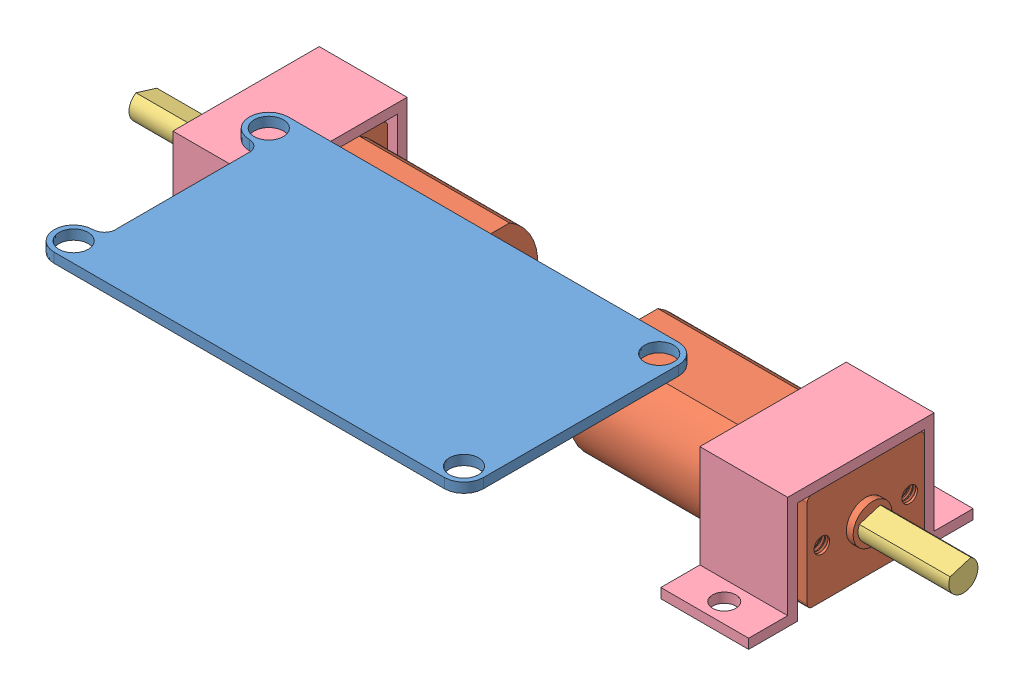
SolidWorks assembly Assem2, configuration Default. Lengths in mm.
Overall size (84 18.94 43.27).
9 component instances, 4 part files, 9 mates.
Components (placement in the parent):
- Spark (Controller)-1: Spark (Controller) [Default] at (-80.2087 -0.5 -49.4214) size (44 1 24)
- Motor_Assembly-1: Motor_Assembly [Default] at (-124.5843 -37.3995 -83.678) x (0 0 1) z (-1 0 0) size (12 10 39.5)
  - Motor_Gearbox-1: Motor_Gearbox [Default] at (14.9911 24.4599 -12.2783) size (12 10 25.9)
  - Motor_Gearbox_Driveshaft-1: Motor_Gearbox_Driveshaft [Default] at (14.9911 24.4599 -41.7783) x (0.956114 0.292994 0) z (0 0 1) size (3 2.5 39.5)
- Motor_Assembly-2: Motor_Assembly [Default] at (-36.0278 -37.3995 -53.6959) x (0 0 -1) z (1 0 0) size (12 10 39.5)
  - Motor_Gearbox-1: Motor_Gearbox [Default] at (14.9911 24.4599 -12.2783) size (12 10 25.9)
  - Motor_Gearbox_Driveshaft-1: Motor_Gearbox_Driveshaft [Default] at (14.9911 24.4599 -41.7783) x (0.956114 0.292994 0) z (0 0 1) size (3 2.5 39.5)
- Motor_Retainer-1: Motor_Retainer [Default] at (-103.306 -18.4396 -69.1869) x (0 0 1) z (-1 0 0) size (23 11.5 9)
- Motor_Retainer-2: Motor_Retainer [Default] at (-48.306 -18.4396 -68.1869) x (0 0 1) z (-1 0 0) size (23 11.5 9)
Mates (geometry in assembly coordinates):
- Coincident1: coincident: plane of Motor_Assembly-1/Motor_Gearbox-1 through (-103.306 -7.9396 -74.1869) normal (0 1 0); plane of Motor_Retainer-1 through (-112.306 -7.9396 -69.1869) normal (0 -1 0)
- Coincident2: coincident: plane of Motor_Assembly-1/Motor_Gearbox-1 through (-103.306 -8.4396 -62.6869) normal (0 0 1); plane of Motor_Retainer-1 through (-112.306 -18.4396 -62.6869) normal (0 0 -1)
- Coincident3: coincident: plane of Motor_Assembly-1/Motor_Gearbox-1 through (-112.306 -17.4396 -63.1869) normal (-1 0 0); plane of Motor_Retainer-1 through (-112.306 -18.4396 -69.1869) normal (-1 0 0)
- Coincident4: coincident: plane of Motor_Assembly-2/Motor_Gearbox-1 through (-48.306 -17.4396 -74.1869) normal (1 0 0); plane of Motor_Retainer-2 through (-48.306 -18.4396 -68.1869) normal (1 0 0)
- Coincident5: coincident: plane of Motor_Assembly-2/Motor_Gearbox-1 through (-57.306 -8.4396 -74.6869) normal (0 0 -1); plane of Motor_Retainer-2 through (-57.306 -18.4396 -74.6869) normal (0 0 1)
- Parallel1: parallel: plane of Motor_Assembly-2/Motor_Gearbox-1 through (-57.306 -8.4396 -62.6869) normal (0 0 1); plane of Motor_Retainer-2 through (-57.306 -18.4396 -61.6869) normal (0 0 -1)
- Coincident7: coincident: plane of Motor_Assembly-2/Motor_Gearbox-1 through (-57.306 -7.9396 -63.1869) normal (0 1 0); plane of Motor_Retainer-2 through (-57.306 -7.9396 -68.1869) normal (0 -1 0)
- Concentric1: concentric: circle of Motor_Assembly-1/Motor_Gearbox_Driveshaft-1; circle of Motor_Assembly-2/Motor_Gearbox_Driveshaft-1
- Distance1: distance = 5 mm: plane of Motor_Assembly-2/Motor_Gearbox_Driveshaft-1 through (-77.806 -12.9396 -68.6869) normal (-1 0 0); plane of Motor_Assembly-1/Motor_Gearbox_Driveshaft-1 through (-82.806 -12.9396 -68.6869) normal (1 0 0)
